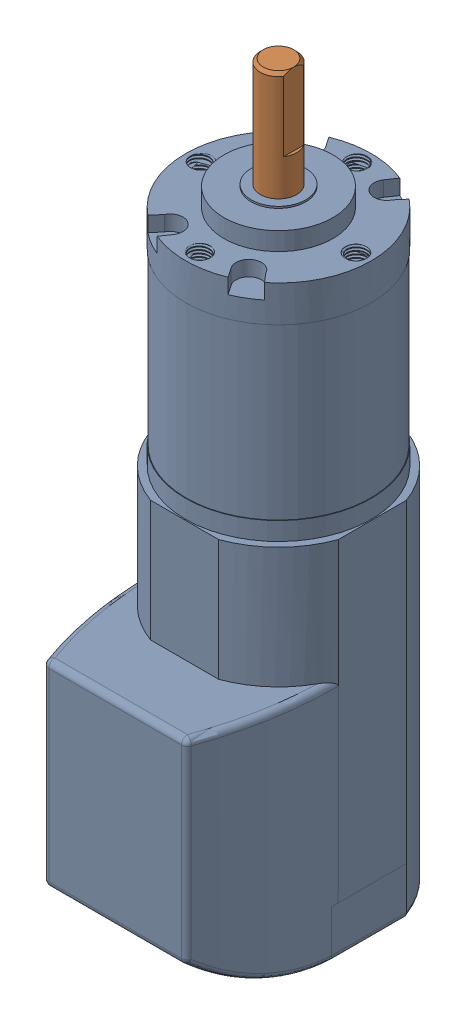
SolidWorks assembly Motor_v1, configuration Default. Lengths in mm.
Overall size (32.95 119.37 42.5).
2 component instances, 2 part files, 2 mates.
Components (placement in the parent):
- Motor_NEW-1: Motor_NEW [Default] at (-50.0322 20.4938 13.7973) size (32.95 101.37 42.5)
- MOTOR SHAFT fede-1: MOTOR SHAFT fede [Default] at (-50.0322 60.7938 13.7973) x (1 0 0) z (0 1 0) size (6 6 18)
Mates (geometry in assembly coordinates):
- Coincident4: coincident: plane of Motor_NEW-1 through (-50.0322 60.7938 13.7973) normal (0 1 0); plane of MOTOR SHAFT-1 through (-62.237 60.7938 -7.8513) normal (0 -1 0)
- Concentric1: concentric aligned: cylinder of Motor_NEW-1 through (-50.0322 60.7938 13.7973) axis (0 -1 0) radius 4.5; cylinder of MOTOR SHAFT-1 through (-50.0322 78.7938 13.7973) axis (0 -1 0) radius 3
